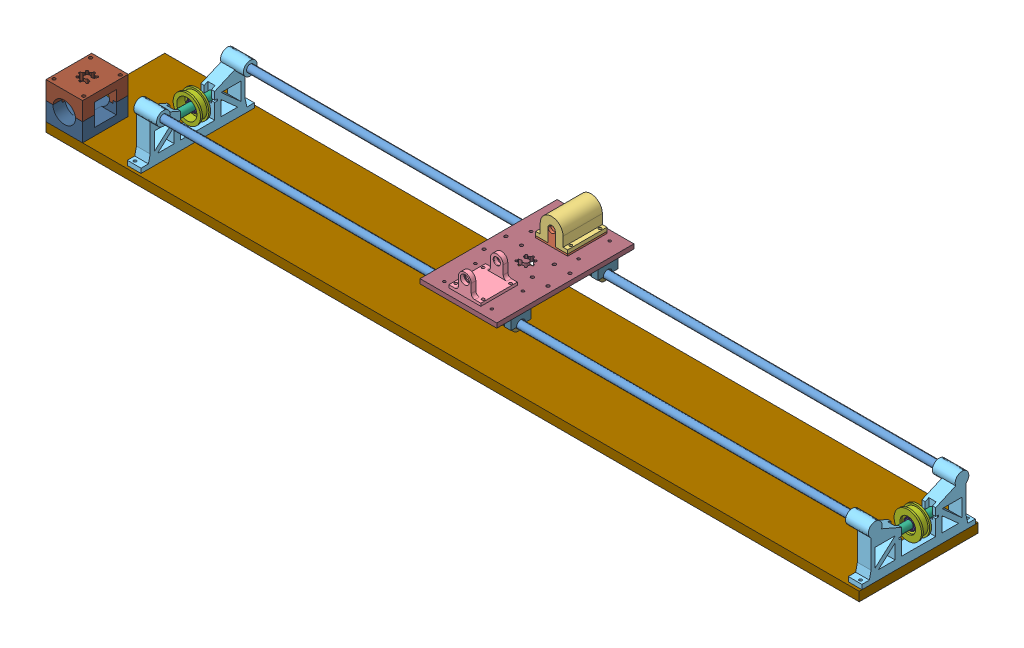
SolidWorks assembly Ensamblaje1, configuration Predeterminado. Lengths in mm.
Overall size (897.5 105 150).
26 component instances, 14 part files, 60 mates.
Components (placement in the parent):
- eje-2: eje [Predeterminado] at (88 60 -112.5) x (1 0 0) z (0 -0.832306 0.554317) size (800 8 8)
- Caja potenciometro-2: Caja potenciometro [Predeterminado] at (459.1145 110.5349 -154.2727) x (1 0 0) z (0 0 -1) size (35 29 43)
  - tapa inferior potenciometro-2: tapa inferior potenciometro [Predeterminado] at (2.2755 17.5349 -59.2727) size (35 17 43)
  - tapa superior potenciometro-2: tapa superior potenciometro [Predeterminado] at (2.2755 18.0349 -21.2727) x (-1 0 0) z (0 0 -1) size (35 27 43)
- sujetador eje-3: sujetador eje [Predeterminado] at (443.89 76 3) size (35 23.5 40)
- eje-3: eje [Predeterminado] at (88 60 -17.5) size (800 8 8)
- Soporte-1: Soporte [Predeterminado] at (890 48.5 -131.5) x (0 -1 0) z (-1 0 0) size (57.5 124 25)
- Soporte-2: Soporte [Predeterminado] at (86 48.5 1.5) x (0 -1 0) z (1 0 0) size (57.5 124 25)
- eje rodamientos-1: eje rodamientos [Predeterminado] at (93.5 38.5 -42.6618) x (0 0 -1) z (1 0 0) size (45 8 8)
- eje rodamientos-2: eje rodamientos [Predeterminado] at (882.5 38.5 -42.6618) x (0 0 -1) z (0.996006 -0.089291 0) size (45 8 8)
- polea rodamiento-1: polea rodamiento [Predeterminado] at (93.5 38.5 -71.6618) size (30 30 11)
- angular contact ball bearing_68_bsi-1: angular contact ball bearing_68_bsi [PreviewCfg] at (93.5 38.5 -68.0743) x (0 0 -1) z (1 0 0) size (3.17 12.7 12.7)
- polea rodamiento-2: polea rodamiento [Predeterminado] at (882.5 38.5 -60.6618) x (-1 0 0) z (0 0 -1) size (30 30 11)
- angular contact ball bearing_68_bsi-2: angular contact ball bearing_68_bsi [PreviewCfg] at (882.5 38.5 -64.2493) x (0 0 -1) z (1 0 0) size (3.17 12.7 12.7)
- Base-1: Base [Predeterminado] at origin size (890 10 130)
- Soporte motor inferior-1: Soporte motor inferior [Predeterminado] at (0 10 0) size (40 20 50)
- soporte motor superior-1: soporte motor superior [Predeterminado] at (40 50 0) x (-1 0 0) z (0 0 1) size (40 23 50)
- Rodamiento LMU8-1: Rodamiento LMU8 [Predeterminado] at (475.39 60 -17.5) size (24 15 15)
- Rodamiento LMU8-2: Rodamiento LMU8 [Predeterminado] at (423.39 60 -112.5) x (1 0 0) z (0 0.457074 0.889429) size (24 15 15)
- Rodamiento LMU8-3: Rodamiento LMU8 [Predeterminado] at (423.39 60 -17.5) size (24 15 15)
- Rodamiento LMU8-4: Rodamiento LMU8 [Predeterminado] at (475.39 60 -112.5) x (1 0 0) z (0 -0.14017 -0.990127) size (24 15 15)
- Base carro acrilico-1: Base carro acrilico [Predeterminado] at (419.39 76 -140) x (1 0 0) z (0 -1 0) size (84 150 5)
- Soporte rodamiento-1: Soporte rodamiento [Predeterminado] at (472.39 71 -28.5) x (1 0 0) z (0 0 -1) size (30 11 46)
- Soporte rodamiento-2: Soporte rodamiento [Predeterminado] at (502.39 71 -101.5) x (-1 0 0) z (0 0 1) size (30 11 46)
- Soporte rodamiento-3: Soporte rodamiento [Predeterminado] at (420.39 71 -123.5) x (1 0 0) z (0 0 -1) size (30 11 46)
- Soporte rodamiento-4: Soporte rodamiento [Predeterminado] at (420.39 71 -28.5) x (1 0 0) z (0 0 -1) size (30 11 46)
Mates (geometry in assembly coordinates):
- Concéntrica4: concentric anti-aligned: circle of Caja potenciometro-2/tapa superior potenciometro-2; cylinder of sujetador eje-3 through (461.39 92.5 -66.9838) axis (0 0 1) radius 5
- Coincidente7: coincident aligned: plane of eje-2 through (888 60 -112.5) normal (1 0 0); plane of eje-3 through (888 60 -17.5) normal (1 0 0)
- Concéntrica6: concentric anti-aligned: circle of eje-3; circle of Soporte-1
- Concéntrica7: concentric anti-aligned: circle of eje-2; circle of Soporte-1
- Coincidente10: coincident anti-aligned: plane of eje-2 through (888 60 -112.5) normal (1 0 0); plane of Soporte-1 through (888 60 -112.5) normal (-1 0 0)
- Concéntrica8: concentric aligned: circle of eje-2; circle of Soporte-2
- Concéntrica9: concentric aligned: circle of eje-3; circle of Soporte-2
- Coincidente14: coincident anti-aligned: plane of eje-3 through (88 60 -17.5) normal (-1 0 0); plane of Soporte-2 through (88 60 -17.5) normal (1 0 0)
- Coincidente15: coincident anti-aligned: plane of Soporte-2 through (97.5 34.5 -87.6618) normal (0 0 1); plane of eje rodamientos-1 through (93.5 38.5 -87.6618) normal (0 0 -1)
- Tangente1: tangent anti-aligned: plane of Soporte-2 through (97.5 34.5 -83.6618) normal (-1 0 0); cylinder of eje rodamientos-1 through (93.5 38.5 -87.6618) axis (0 0 1) radius 4
- Tangente2: tangent anti-aligned: plane of Soporte-2 through (86 34.5 1.5) normal (0 1 0); cylinder of eje rodamientos-1 through (93.5 38.5 -87.6618) axis (0 0 1) radius 4
- Tangente4: tangent anti-aligned: plane of Soporte-1 through (890 34.5 -131.5) normal (0 1 0); cylinder of eje rodamientos-2 through (882.5 38.5 -87.6618) axis (0 0 1) radius 4
- Coincidente16: coincident anti-aligned: plane of Soporte-1 through (886.5 34.5 -87.6618) normal (0 0 1); plane of eje rodamientos-2 through (882.5 38.5 -87.6618) normal (0 0 -1)
- Tangente6: tangent anti-aligned: plane of Soporte-1 through (878.5 34.5 -87.6618) normal (1 0 0); cylinder of eje rodamientos-2 through (882.5 38.5 -87.6618) axis (0 0 1) radius 4
- Concéntrica12: concentric aligned: cylinder of polea rodamiento-1 through (93.5 38.5 -62.6618) axis (0 0 -1) radius 11; cylinder of angular contact ball bearing_68_bsi-1 through (93.5 38.5 -47.4368) axis (0 0 -1) radius 3.175
- Concéntrica13: concentric anti-aligned: cylinder of polea rodamiento-2 through (882.5 38.5 -69.6618) axis (0 0 1) radius 11; cylinder of angular contact ball bearing_68_bsi-2 through (882.5 38.5 -43.6118) axis (0 0 -1) radius 6.35
- Coincidente17: coincident anti-aligned: plane of polea rodamiento-2 through (882.5 38.5 -62.6618) normal (0 0 -1); plane of angular contact ball bearing_68_bsi-2 through (882.5 44.19 -62.6618) normal (0 0 1)
- Coincidente18: coincident anti-aligned: plane of polea rodamiento-1 through (93.5 38.5 -69.6618) normal (0 0 1); plane of angular contact ball bearing_68_bsi-1 through (93.5 44.723 -69.6618) normal (0 0 -1)
- Concéntrica14: concentric anti-aligned: cylinder of eje rodamientos-2 through (882.5 38.5 -87.6618) axis (0 0 1) radius 4; circle of polea rodamiento-2
- Concéntrica15: concentric aligned: cylinder of eje rodamientos-1 through (93.5 38.5 -87.6618) axis (0 0 1) radius 4; circle of polea rodamiento-1
- Distancia1: distance = 12 mm anti-aligned: plane of polea rodamiento-1 through (93.5 38.5 -71.6618) normal (0 0 -1); plane of Soporte-2 through (101 39 -83.6618) normal (0 0 1)
- Distancia2: distance = 12 mm anti-aligned: plane of polea rodamiento-2 through (882.5 38.5 -71.6618) normal (0 0 -1); plane of Soporte-1 through (875 39 -83.6618) normal (0 0 1)
- Coincidente19: coincident anti-aligned: plane of Soporte-1 through (875 10 -10) normal (0 -1 0); plane of Base-1 through (0 10 0) normal (0 1 0)
- Distancia3: distance = 3 mm aligned: plane of Soporte-1 through (875 10 -3) normal (0 0 1); plane of Base-1 through (0 10 0) normal (0 0 1)
- Coincidente21: coincident aligned: plane of Soporte-1 through (890 60 -112.5) normal (1 0 0); plane of Base-1 through (890 10 0) normal (1 0 0)
- Coincidente22: coincident anti-aligned: plane of Base-1 through (0 10 0) normal (0 1 0); plane of Soporte motor inferior-1 through (0 10 0) normal (0 -1 0)
- Coincidente23: coincident aligned: plane of Base-1 through (0 10 0) normal (0 0 1); plane of Soporte motor inferior-1 through (0 30 0) normal (0 0 1)
- Coincidente24: coincident anti-aligned: plane of Soporte motor inferior-1 through (0 30 0) normal (0 1 0); plane of soporte motor superior-1 through (40 30 0) normal (0 -1 0)
- Coincidente25: coincident aligned: plane of Soporte motor inferior-1 through (0 30 0) normal (0 0 1); plane of soporte motor superior-1 through (40 30 0) normal (0 0 1)
- Coincidente26: coincident aligned: plane of Soporte motor inferior-1 through (0 30 0) normal (-1 0 0); plane of soporte motor superior-1 through (0 30 0) normal (-1 0 0)
- Concéntrica16: concentric aligned: cylinder of eje-2 through (888 60 -112.5) axis (-1 0 0) radius 4; circle of Rodamiento LMU8-2
- Concéntrica17: concentric aligned: cylinder of eje-2 through (888 60 -112.5) axis (-1 0 0) radius 4; circle of Rodamiento LMU8-4
- Concéntrica18: concentric aligned: cylinder of eje-3 through (888 60 -17.5) axis (-1 0 0) radius 4; circle of Rodamiento LMU8-3
- Concéntrica19: concentric aligned: cylinder of eje-3 through (888 60 -17.5) axis (-1 0 0) radius 4; circle of Rodamiento LMU8-1
- Coincidente27: coincident aligned: plane of Base-1 through (0 0 0) normal (0 0 1); plane of assembly through (0 0 0) normal (0 0 1)
- Coincidente28: coincident aligned: plane of Base-1 through (0 0 0) normal (0 1 0); plane of assembly through (0 0 0) normal (0 1 0)
- Coincidente29: coincident aligned: plane of Base-1 through (0 0 0) normal (1 0 0); plane of assembly through (0 0 0) normal (1 0 0)
- Coincidente30: coincident aligned: plane of Base-1 through (0 10 0) normal (-1 0 0); plane of Soporte motor inferior-1 through (0 30 0) normal (-1 0 0)
- Concéntrica20: concentric anti-aligned: circle of Base carro acrilico-1; circle of Soporte rodamiento-4
- Concéntrica21: concentric anti-aligned: circle of Base carro acrilico-1; circle of Soporte rodamiento-4
- Coincidente31: coincident anti-aligned: plane of Base carro acrilico-1 through (419.39 71 -140) normal (0 -1 0); plane of Soporte rodamiento-4 through (420.39 71 -28.5) normal (0 1 0)
- Concéntrica22: concentric anti-aligned: circle of Base carro acrilico-1; circle of Soporte rodamiento-1
- Concéntrica23: concentric anti-aligned: circle of Base carro acrilico-1; circle of Soporte rodamiento-1
- Coincidente33: coincident anti-aligned: plane of Base carro acrilico-1 through (419.39 71 -140) normal (0 -1 0); plane of Soporte rodamiento-1 through (472.39 71 -28.5) normal (0 1 0)
- Concéntrica24: concentric anti-aligned: circle of Base carro acrilico-1; circle of Soporte rodamiento-3
- Concéntrica25: concentric anti-aligned: circle of Base carro acrilico-1; circle of Soporte rodamiento-3
- Coincidente35: coincident anti-aligned: plane of Base carro acrilico-1 through (419.39 71 -140) normal (0 -1 0); plane of Soporte rodamiento-3 through (420.39 71 -123.5) normal (0 1 0)
- Concéntrica26: concentric anti-aligned: circle of Base carro acrilico-1; circle of Soporte rodamiento-2
- Concéntrica27: concentric anti-aligned: circle of Base carro acrilico-1; circle of Soporte rodamiento-2
- Coincidente36: coincident anti-aligned: plane of Base carro acrilico-1 through (419.39 71 -140) normal (0 -1 0); plane of Soporte rodamiento-2 through (502.39 71 -101.5) normal (0 1 0)
- Coincidente43: coincident anti-aligned: plane of Caja potenciometro-2/tapa inferior potenciometro-2 through (458.89 76 -133) normal (0 -1 0); plane of Base carro acrilico-1 through (419.39 76 -140) normal (0 1 0)
- Concéntrica37: concentric aligned: circle of Caja potenciometro-2/tapa superior potenciometro-2; circle of Base carro acrilico-1
- Concéntrica38: concentric aligned: circle of Caja potenciometro-2/tapa inferior potenciometro-2; circle of Base carro acrilico-1
- Concéntrica39: concentric anti-aligned: circle of sujetador eje-3; circle of Base carro acrilico-1
- Concéntrica40: concentric aligned: cylinder of eje-3 through (888 60 -17.5) axis (-1 0 0) radius 4; circle of Soporte rodamiento-1
- Concéntrica41: concentric anti-aligned: cylinder of eje-2 through (888 60 -112.5) axis (-1 0 0) radius 4; circle of Soporte rodamiento-2
- Coincidente47: coincident anti-aligned: plane of Rodamiento LMU8-1 through (499.39 64 -17.5) normal (1 0 0); plane of Soporte rodamiento-1 through (499.39 60 -28.5) normal (-1 0 0)
- Coincidente48: coincident anti-aligned: plane of Rodamiento LMU8-3 through (423.39 67.5 -17.5) normal (-1 0 0); plane of Soporte rodamiento-4 through (423.39 60 -17.5) normal (1 0 0)
- Coincidente49: coincident anti-aligned: plane of Rodamiento LMU8-4 through (499.39 56.0395 -111.9393) normal (1 0 0); plane of Soporte rodamiento-2 through (499.39 60 -112.5) normal (-1 0 0)
- Coincidente50: coincident anti-aligned: plane of Rodamiento LMU8-2 through (423.39 66.6707 -115.9281) normal (-1 0 0); plane of Soporte rodamiento-3 through (423.39 60 -112.5) normal (1 0 0)
